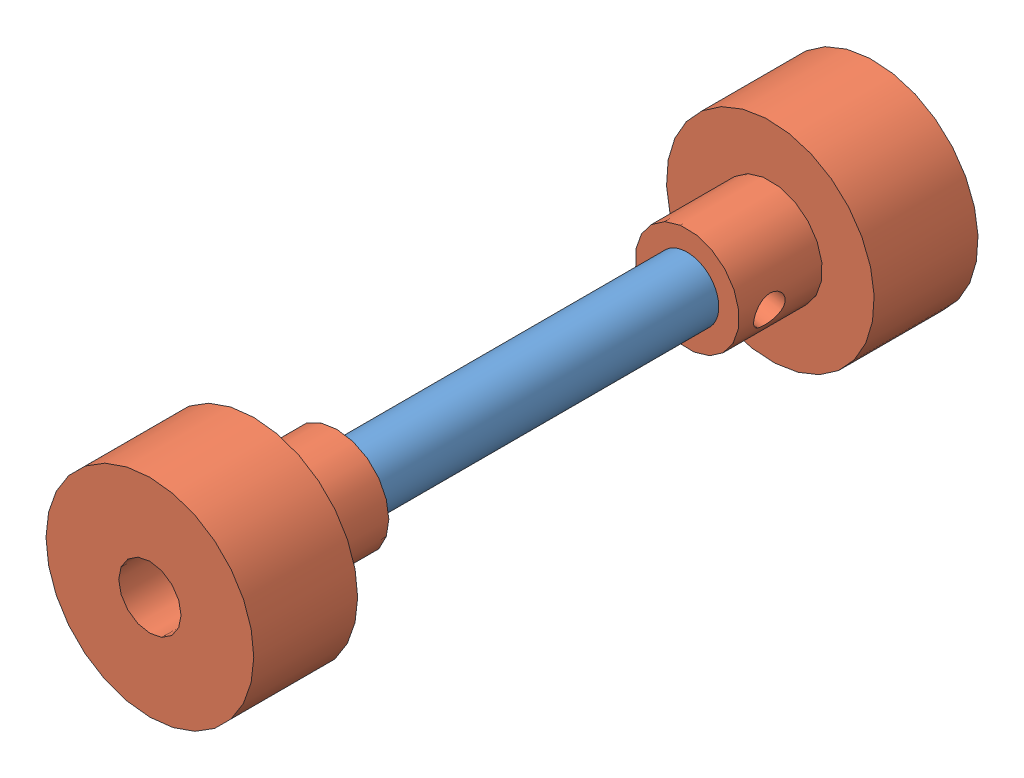
SolidWorks assembly final back wheel system, configuration Default. Lengths in mm.
Overall size (356.07 356.07 1065.97).
3 component instances, 2 part files, 4 mates.
Components (placement in the parent):
- back wheel axle-1: back wheel axle [Default] at (608.4896 1160.9675 538.3968) x (0.998292 -0.058423 0) z (0 0 1) size (93 93 537.88)
- wheel big updated-2: wheel big updated [Default] at (608.2446 1161.0123 -155.8925) x (-0.179961 -0.983674 0) z (0 0 -1) size (306 306 275.4)
- wheel big updated-3: wheel big updated [Default] at (607.7023 1162.5175 716.4696) x (1 -0.000734 0) z (0 0 1) size (306 306 275.4)
Mates (geometry in assembly coordinates):
- Concentric2: concentric aligned: circle of back wheel axle-1; circle of wheel big updated-2
- Coincident2: coincident aligned: circle of back wheel axle-1
- Concentric4: concentric aligned: circle of back wheel axle-1; circle of wheel big updated-2
- Coincident3: coincident anti-aligned: plane of back wheel axle-1 through (608.4896 1160.9675 537.8755) normal (0 0 1); circle of wheel big updated-3
